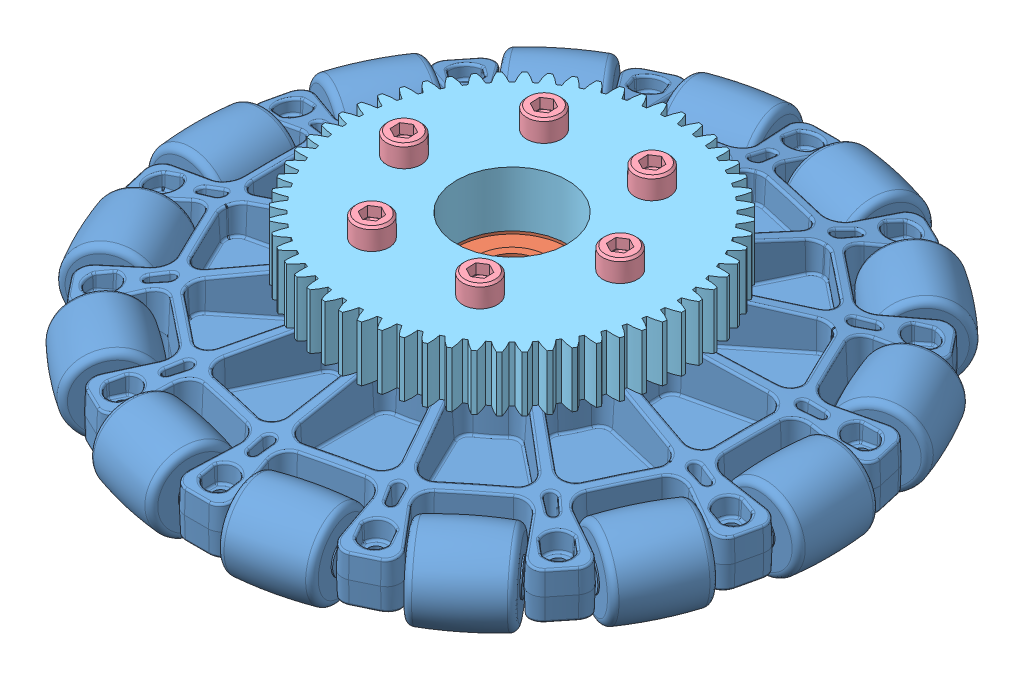
SolidWorks assembly omni_wheel_assm_geared, configuration Default. Lengths in mm.
Overall size (152.04 49.28 152.39).
10 component instances, 5 part files, 7 mates.
Components (placement in the parent):
- 6inch_omni-1: 6inch_omni [Default] at (-5.8198 16.297 -20.6554) size (152.04 25.4 152.39)
- plain 0500 bearing-1: plain 0500 bearing [Default] at (-5.8198 37.7283 -20.6554) x (1 0 0) z (0 1 0) size (28.57 28.57 7.94)
- flanged 0500 bearing-1: flanged 0500 bearing [Default] at (-5.8198 18.6783 -20.6554) x (0.923728 0 -0.383049) z (0 -1 0) size (31.75 31.75 7.94)
- Socket Head Cap Screw_AI-3: Socket Head Cap Screw_AI [HX-SHCS 0.19-32x1.75x1.75-C] at (-16.8455 59.223 0.4507) x (0 -1 0) z (0.99911 0 -0.042182) size (49.28 7.94 7.94)
- gear, 60t-1: gear, 60t [Default] at (-5.8198 41.697 -20.6554) x (1 0 0) z (0 -1 0) size (78.74 78.74 12.7)
- Socket Head Cap Screw_AI-7: Socket Head Cap Screw_AI [HX-SHCS 0.19-32x1.75x1.75-C] at (-29.6111 59.223 -19.651) x (0 -1 0) z (0.536085 0 0.844164) size (49.28 7.94 7.94)
- Socket Head Cap Screw_AI-8: Socket Head Cap Screw_AI [HX-SHCS 0.19-32x1.75x1.75-C] at (-18.5853 59.223 -40.7571) x (0 -1 0) z (-0.463025 0 0.886345) size (49.28 7.94 7.94)
- Socket Head Cap Screw_AI-9: Socket Head Cap Screw_AI [HX-SHCS 0.19-32x1.75x1.75-C] at (5.206 59.223 -41.7615) x (0 -1 0) z (-0.99911 0 0.042182) size (49.28 7.94 7.94)
- Socket Head Cap Screw_AI-10: Socket Head Cap Screw_AI [HX-SHCS 0.19-32x1.75x1.75-C] at (17.9715 59.223 -21.6599) x (0 -1 0) z (-0.536085 0 -0.844164) size (49.28 7.94 7.94)
- Socket Head Cap Screw_AI-11: Socket Head Cap Screw_AI [HX-SHCS 0.19-32x1.75x1.75-C] at (6.9458 59.223 -0.5538) x (0 -1 0) z (0.463025 0 -0.886345) size (49.28 7.94 7.94)
Mates (geometry in assembly coordinates):
- Concentric9: concentric anti-aligned: cylinder of 6inch_omni-1 through (-5.8198 34.077 -20.6554) axis (0 -1 0) radius 14.2812; cylinder of plain 0500 bearing-1 through (-5.8198 37.7283 -20.6554) axis (0 1 0) radius 14.2875
- Coincident8: coincident aligned: plane of 6inch_omni-1 through (-64.3668 41.697 -27.1324) normal (0 1 0); plane of plain 0500 bearing-1 through (-5.0809 41.697 -20.6554) normal (0 1 0)
- Concentric10: concentric anti-aligned: cylinder of 6inch_omni-1 through (-5.8198 23.917 -20.6554) axis (0 1 0) radius 14.2812; cylinder of flanged 0500 bearing-1 through (-5.8198 18.6783 -20.6554) axis (0 -1 0) radius 14.2875
- Coincident9: coincident anti-aligned: plane of 6inch_omni-1 through (-64.3668 16.297 -14.1784) normal (0 -1 0); plane of flanged 0500 bearing-1 through (-4.4867 16.297 -21.2083) normal (0 1 0)
- Concentric20: concentric anti-aligned: circle of plain 0500 bearing-1; circle of gear, 60t-1
- Coincident27: coincident anti-aligned: plane of plain 0500 bearing-1 through (-5.0809 41.697 -20.6554) normal (0 1 0); plane of gear, 60t-1 through (-5.8198 41.697 -20.6554) normal (0 -1 0)
- Coincident28: coincident anti-aligned: plane of Socket Head Cap Screw_AI-3 through (-17.013 54.397 -3.5146) normal (0 -1 0); plane of gear, 60t-1 through (-5.8198 54.397 -20.6554) normal (0 1 0)
